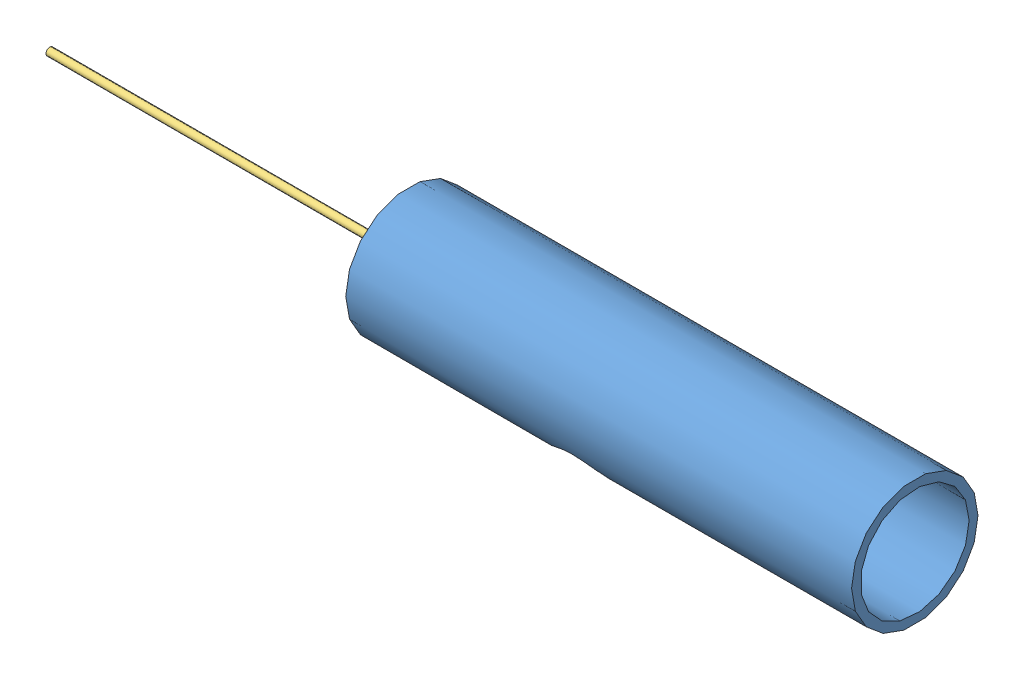
SolidWorks assembly uncompressed+Ball, configuration Default. Lengths in mm.
Overall size (342 50 50).
4 component instances, 4 part files, 7 mates.
Components (placement in the parent):
- tube-1: tube [Default] at origin size (200 50 50)
- front plate-1: front plate [Default] at (158 0.3772 0) size (5 30 30)
- backplate-2: backplate [Default] at (-142 0.3772 0) size (300 3 3)
- Part2-2: Part2 [Default] at (10 0 0) x (0 -1 0) z (0 0 1) size (40.62 154.94 40.14)
Mates (geometry in assembly coordinates):
- Distance2: distance = 10 mm: point of Part2-2; point of assembly
- Coincident4: coincident anti-aligned: plane of tube-1 through (0 0 0) normal (0 1 0); plane of Part2-2
- Coincident5: coincident aligned: plane of tube-1 through (0 0 0) normal (0 0 1); plane of Part2-2 through (10 0 0) normal (0 0 1)
- Distance4: distance = 148 mm anti-aligned: plane of front plate-1 through (158 0.3772 0) normal (-1 0 0); plane of tube-1 through (10 0 0) normal (1 0 0)
- Coincident8: coincident aligned: plane of front plate-1 through (158 0.3772 0) normal (0 0 1); plane of Part2-2 through (10 0 0) normal (0 0 1)
- Coincident9: coincident anti-aligned: plane of front plate-1 through (158 0.3772 0) normal (-1 0 0); plane of backplate-2 through (158 0.3772 0) normal (1 0 0)
- Distance5: distance = 300 mm: point of backplate-2; point of front plate-1
